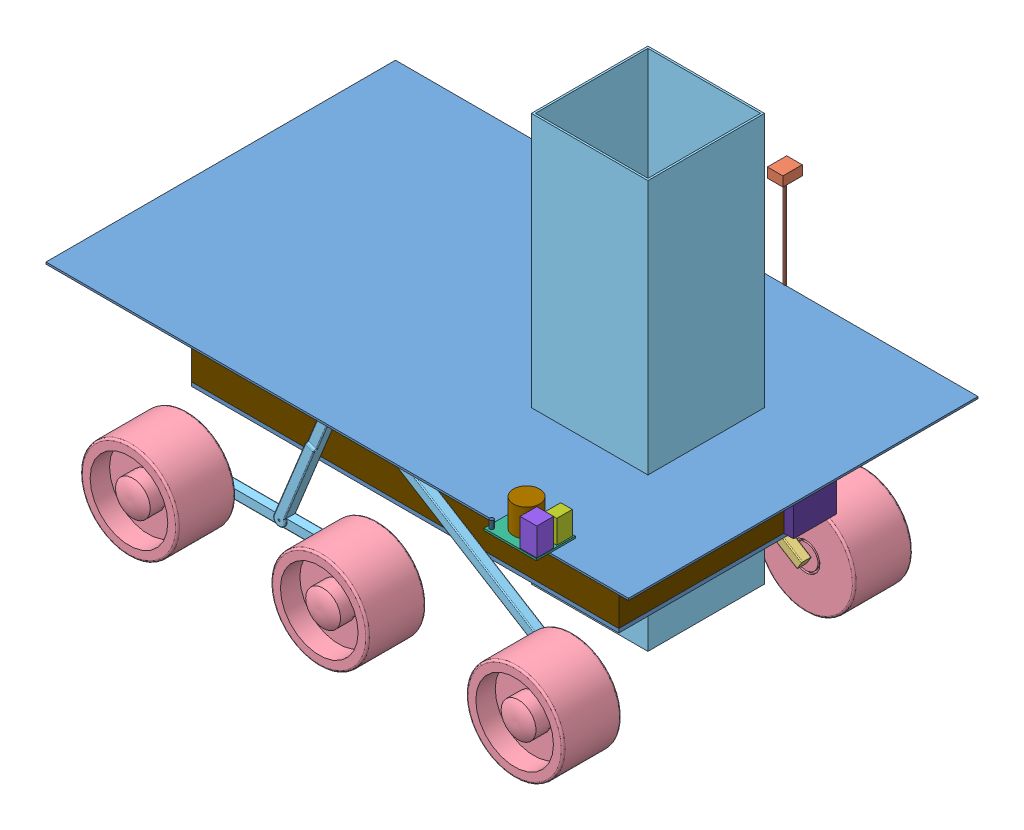
SolidWorks assembly layout_Assem_with_cover_rev2, configuration Default. Lengths in mm.
Overall size (3000 2527.52 1982.36).
39 component instances, 28 part files, 43 mates.
Components (placement in the parent):
- Rover_base-1: Rover_base [Default] at (-1064.6676 -0.8898 562.4151) size (2200 20 1100)
- Neutron_spectrometer-1: Neutron_spectrometer [Default] at (-926.7762 19.1102 412.2415) size (300 57 300)
- Neutron_spectrometer_electronics-1: Neutron_spectrometer_electronics [Default] at (-591.6675 19.1102 476.7062) size (180 30 130)
- gc-1: gc [Default] at (-1085.6976 19.1102 139.436) size (100 80 100)
- svr_box-1: svr_box [Default] at (435.3324 -257.9063 312.4151) size (600 2100 600)
- xrf-1: xrf [Default] at (-995.9409 19.1102 -179.1913) size (80 90 80)
- geotechnical_exp-1: geotechnical_exp [Default] at (118.8439 19.1102 479.7148) x (0.999975 0 -0.007135) z (0.007135 0 0.999975) size (130 30 130)
- penetrometer_3-1: penetrometer_3 [Default] at (226.7911 19.1102 -521.6787) x (-0.361814 0 0.93225) z (-0.93225 0 -0.361814) size (20 40 20)
- penetrometer_3-2: penetrometer_3 [Default] at (171.3766 19.1102 -523.8951) size (20 40 20)
- penetrometer_3-3: penetrometer_3 [Default] at (128.071 19.1102 -518.5402) x (0.588244 0 -0.808683) z (0.808683 0 0.588244) size (20 40 20)
- power-1: power [Default] at (-492.3956 19.1102 -328.3877) size (180 90 96)
- geotechnical_exp_vane-1: geotechnical_exp_vane [Default] at (965.2252 19.1102 444.9326) size (220 40 220)
- Magnents-1: Magnents [Default] at (-1020.4169 -10.8898 98.2252) size (45 10 45)
- Becon-1: Becon [Default] at (656.9367 19.1102 515.9957) size (80 90 100)
- Belly Cam-1: Belly Cam [Default] at (-624.94 -100.8898 134.6139) size (150 100 150)
- lithium_battery_pack-1: lithium_battery_pack [Default] at (-598.6676 19.1102 301.6649) size (984 426 582)
- arm-1: arm [Default] at (-1208.8877 19.1102 -520.2644) x (-1 0 0) z (0 0 -1) size (1100 100 100)
- scoop-1: scoop [Default] at (-1258.8868 69.4182 -520.2644) x (0.225074 0.974342 0) z (0.974342 -0.225074 0) size (211.36 101.82 100)
- drill-1: drill [Default] at (1185.3324 19.1102 -287.5849) size (500 200 220)
- Rover_base_cover_rev2-1: Rover_base_cover_rev2 [Default] at (1135.3324 519.1102 -537.5849) x (1 0 0) z (0 0 -1) size (2200 500 1100)
- solar cell-1: solar cell [Default] at (-1464.6676 519.1102 -887.5849) x (-1 0 0) z (0 0 -1) size (3000 10 1800)
- stero_imaging_sys-1: stero_imaging_sys [Default] at (532.9681 509.1102 -537.5849) size (80 548.91 402.36)
- left_mobiiity_assemSLDASM-1: left_mobiiity_assemSLDASM [Default] at (441.8491 -174.8256 -588.2789) x (-1 0 0) z (0 0 -1) size (2690.28 1092.83 400.39)
  - Suspension arms-1: Suspension arms [Default] at (-510.2208 -182.1885 -50.694) size (2026.29 764.42 130)
  - wheel-1: wheel [Default] at (-506.5103 -152.4189 299.306) x (-0.792605 -0.609735 0) z (0 0 -1) size (500 500 300.39)
  - wheel-2: wheel [Default] at (1479.7792 -157.1885 299.306) x (-0.72713 -0.6865 0) z (0 0 -1) size (500 500 300.39)
  - wheel-3: wheel [Default] at (499.7792 -157.1885 299.306) x (-0.949229 -0.314586 0) z (0 0 -1) size (500 500 300.39)
- right_mobiiity_assemSLDASM-1: right_mobiiity_assemSLDASM [Default] at (616.9237 -382.4876 815.2315) x (-1 0 0) z (0 0 -1) size (2486.29 989.42 400.39)
  - Suspension arms_mirror-1: Suspension arms_mirror [Default] at (-335.6808 35.7938 152.8164) size (2026.29 764.42 130)
  - wheel-1: wheel [Default] at (1654.3192 60.7938 -97.1836) size (500 500 300.39)
  - wheel-2: wheel [Default] at (-331.9703 65.5634 -97.1836) size (500 500 300.39)
  - wheel-3: wheel [Default] at (674.3192 60.7938 -97.1836) size (500 500 300.39)
- GN&C_assem-1: GN&C_assem [Default] at (920.8947 589.1102 1042.4151) x (0 0 1) z (-1 0 0) size (480 252.24 270.29)
  - mount-1: mount [Default] at origin size (480 110 270.29)
  - descent imager-1: descent imager [Default] at (-111.5702 10 -203.4147) size (80 120 60)
  - Radar Altimeter-1: Radar Altimeter [Default] at (-90.262 10 -182.0396) size (86.36 142.24 86.36)
  - Star Tracker-1: Star Tracker [Default] at (-109.408 10 -109.8916) size (135 142 135)
  - sun sensor_2-1: sun sensor_2 [Default] at (-20.8013 10 -18.8431) x (0.996981 0 0.07765) z (-0.07765 0 0.996981) size (20 40 20)
  - sun sensor_2-2: sun sensor_2 [Default] at (-179.5135 10 -13.6063) size (20 40 20)
Mates (geometry in assembly coordinates):
- Coincident2: coincident anti-aligned: plane of Rover_base-1 through (-1064.6676 19.1102 -537.5849) normal (0 1 0); plane of Neutron_spectrometer-1 through (-926.7762 19.1102 412.2415) normal (0 -1 0)
- Coincident6: coincident anti-aligned: plane of Rover_base-1 through (-1064.6676 19.1102 -537.5849) normal (0 1 0); plane of Neutron_spectrometer_electronics-1 through (-591.6675 19.1102 346.7062) normal (0 -1 0)
- Coincident7: coincident anti-aligned: plane of Rover_base-1 through (-1064.6676 19.1102 -537.5849) normal (0 1 0); plane of power-1 through (-492.3956 19.1102 -424.3877) normal (0 -1 0)
- Coincident8: coincident anti-aligned: plane of Rover_base-1 through (-1064.6676 19.1102 -537.5849) normal (0 1 0); plane of gc-1 through (-1085.6976 19.1102 39.436) normal (0 -1 0)
- Coincident9: coincident aligned: plane of Rover_base-1 through (-1064.6676 19.1102 -537.5849) normal (0 1 0); circle of geotechnical_exp-1 centre (118.8439 19.1102 479.7148) axis (0 1 0)
- Coincident10: coincident anti-aligned: plane of Rover_base-1 through (-1064.6676 19.1102 -537.5849) normal (0 1 0); plane of xrf-1 through (-995.9409 19.1102 -179.1913) normal (0 -1 0)
- Coincident11: coincident aligned: plane of Rover_base-1 through (-1064.6676 19.1102 -537.5849) normal (0 1 0); circle of penetrometer_3-3 centre (128.071 19.1102 -518.5402) axis (0 1 0)
- Coincident12: coincident anti-aligned: plane of Rover_base-1 through (-1064.6676 19.1102 -537.5849) normal (0 1 0); plane of penetrometer_3-2 through (171.3766 19.1102 -523.8951) normal (0 -1 0)
- Coincident13: coincident aligned: plane of Rover_base-1 through (-1064.6676 19.1102 -537.5849) normal (0 1 0); circle of penetrometer_3-1 centre (226.7911 19.1102 -521.6787) axis (0 1 0)
- Coincident14: coincident anti-aligned: plane of Rover_base-1 through (-1064.6676 19.1102 -537.5849) normal (0 1 0); plane of geotechnical_exp_vane-1 through (965.2252 19.1102 444.9326) normal (0 -1 0)
- Coincident15: coincident anti-aligned: plane of Rover_base-1 through (-1064.6676 -0.8898 -537.5849) normal (0 -1 0); plane of Magnents-1 through (-1020.4169 -0.8898 98.2252) normal (0 1 0)
- Coincident16: coincident anti-aligned: plane of Rover_base-1 through (-1064.6676 19.1102 -537.5849) normal (0 1 0); plane of Becon-1 through (656.9367 19.1102 515.9957) normal (0 -1 0)
- Coincident18: coincident: line of Rover_base-1; plane of svr_box-1 through (435.3324 1842.0937 312.4151) normal (-1 0 0)
- Coincident20: coincident: line of Rover_base-1; plane of svr_box-1 through (435.3324 1842.0937 -287.5849) normal (0 0 -1)
- Perpendicular2: perpendicular: line of Rover_base-1; line of svr_box-1
- Perpendicular3: perpendicular: line of Rover_base-1; line of svr_box-1
- Perpendicular4: perpendicular: line of Rover_base-1; line of svr_box-1
- Coincident21: coincident anti-aligned: plane of Rover_base-1 through (-1064.6676 19.1102 -537.5849) normal (0 1 0); plane of lithium_battery_pack-1 through (-598.6676 19.1102 -280.3351) normal (0 -1 0)
- Distance1: distance = 50 mm anti-aligned: plane of svr_box-1 through (435.3324 1842.0937 312.4151) normal (-1 0 0); plane of lithium_battery_pack-1 through (385.3324 445.1102 301.6649) normal (1 0 0)
- Coincident23: coincident anti-aligned: plane of Rover_base-1 through (-1064.6676 19.1102 -537.5849) normal (0 1 0); plane of arm-1 through (-1208.8877 19.1102 -420.2644) normal (0 -1 0)
- Distance2: distance = 100 mm: line of Rover_base-1; point of arm-1
- Distance3: distance = 20 mm: line of Rover_base-1; line of arm-1
- Coincident27: coincident aligned: circle of arm-1 centre (-1208.8877 69.1102 -470.2644) axis (0 0 1); circle of scoop-1 centre (-1208.8877 69.1102 -470.2644) axis (0 0 1)
- Coincident28: coincident anti-aligned: plane of Rover_base-1 through (-1064.6676 19.1102 -537.5849) normal (0 1 0); plane of drill-1 through (1185.3324 19.1102 -507.5849) normal (0 -1 0)
- Coincident29: coincident anti-aligned: plane of svr_box-1 through (435.3324 1842.0937 -287.5849) normal (0 0 -1); plane of drill-1 through (1185.3324 219.1102 -287.5849) normal (0 0 1)
- Distance4: distance = 50 mm: line of Rover_base-1; plane of drill-1 through (1185.3324 219.1102 -287.5849) normal (1 0 0)
- Coincident30: coincident anti-aligned: plane of svr_box-1 through (435.3324 1842.0937 312.4151) normal (-1 0 0); plane of Rover_base_cover_rev2-1 through (435.3324 119.1102 -287.5849) normal (1 0 0)
- Coincident31: coincident anti-aligned: plane of svr_box-1 through (435.3324 1842.0937 312.4151) normal (0 0 1); plane of Rover_base_cover_rev2-1 through (1035.3324 119.1102 312.4151) normal (0 0 -1)
- Coincident32: coincident anti-aligned: plane of Rover_base-1 through (-1064.6676 19.1102 -537.5849) normal (0 1 0); plane of Rover_base_cover_rev2-1 through (1135.3324 19.1102 562.4151) normal (0 -1 0)
- Coincident33: coincident anti-aligned: plane of Rover_base_cover_rev2-1 through (1135.3324 519.1102 562.4151) normal (0 1 0); plane of solar cell-1 through (-1464.6676 519.1102 -887.5849) normal (0 -1 0)
- Coincident34: coincident anti-aligned: plane of svr_box-1 through (435.3324 1842.0937 312.4151) normal (-1 0 0); plane of solar cell-1 through (435.3324 519.1102 -287.5849) normal (1 0 0)
- Coincident35: coincident anti-aligned: plane of svr_box-1 through (435.3324 1842.0937 312.4151) normal (0 0 1); plane of solar cell-1 through (435.3324 519.1102 312.4151) normal (0 0 -1)
- Coincident36: coincident anti-aligned: plane of Rover_base_cover_rev2-1 through (1135.3324 19.1102 -537.5849) normal (0 0 -1); plane of stero_imaging_sys-1 through (542.9681 519.1102 -537.5849) normal (0 0 1)
- Coincident37: coincident anti-aligned: plane of solar cell-1 through (-1464.6676 519.1102 -887.5849) normal (0 -1 0); plane of stero_imaging_sys-1 through (542.9681 519.1102 -884.9456) normal (0 1 0)
- Coincident38: coincident anti-aligned: plane of Rover_base_cover_rev2-1 through (1135.3324 19.1102 -537.5849) normal (0 0 -1); plane of left_mobiiity_assemSLDASM-1/Suspension arms-1 through (-219.8802 300.4813 -537.5849) normal (0 0 1)
- Parallel1: parallel anti-aligned: line of Rover_base-1; line of left_mobiiity_assemSLDASM-1/Suspension arms-1
- Distance7: distance = 650 mm: line of Rover_base_cover_rev2-1; point of left_mobiiity_assemSLDASM-1/Suspension arms-1
- Coincident43: coincident anti-aligned: plane of Rover_base_cover_rev2-1 through (1135.3324 19.1102 562.4151) normal (0 0 1); plane of right_mobiiity_assemSLDASM-1/Suspension arms_mirror-1 through (-219.3456 310.8016 562.4151) normal (0 0 -1)
- Parallel2: parallel anti-aligned: line of Rover_base-1; line of right_mobiiity_assemSLDASM-1/Suspension arms_mirror-1
- Coincident44: coincident anti-aligned: plane of Rover_base_cover_rev2-1 through (1135.3324 19.1102 562.4151) normal (0 0 1); plane of GN&C_assem-1/mount-1 through (1050.8947 489.1102 562.4151) normal (0 0 -1)
- Coincident45: coincident anti-aligned: plane of solar cell-1 through (-1464.6676 519.1102 -887.5849) normal (0 -1 0); plane of GN&C_assem-1/mount-1 through (1050.8947 519.1102 562.4151) normal (0 1 0)
- Distance8: distance = 300 mm: line of Rover_base-1; line of right_mobiiity_assemSLDASM-1/Suspension arms_mirror-1
- Distance9: distance = 650 mm: line of Rover_base_cover_rev2-1; point of right_mobiiity_assemSLDASM-1/Suspension arms_mirror-1
